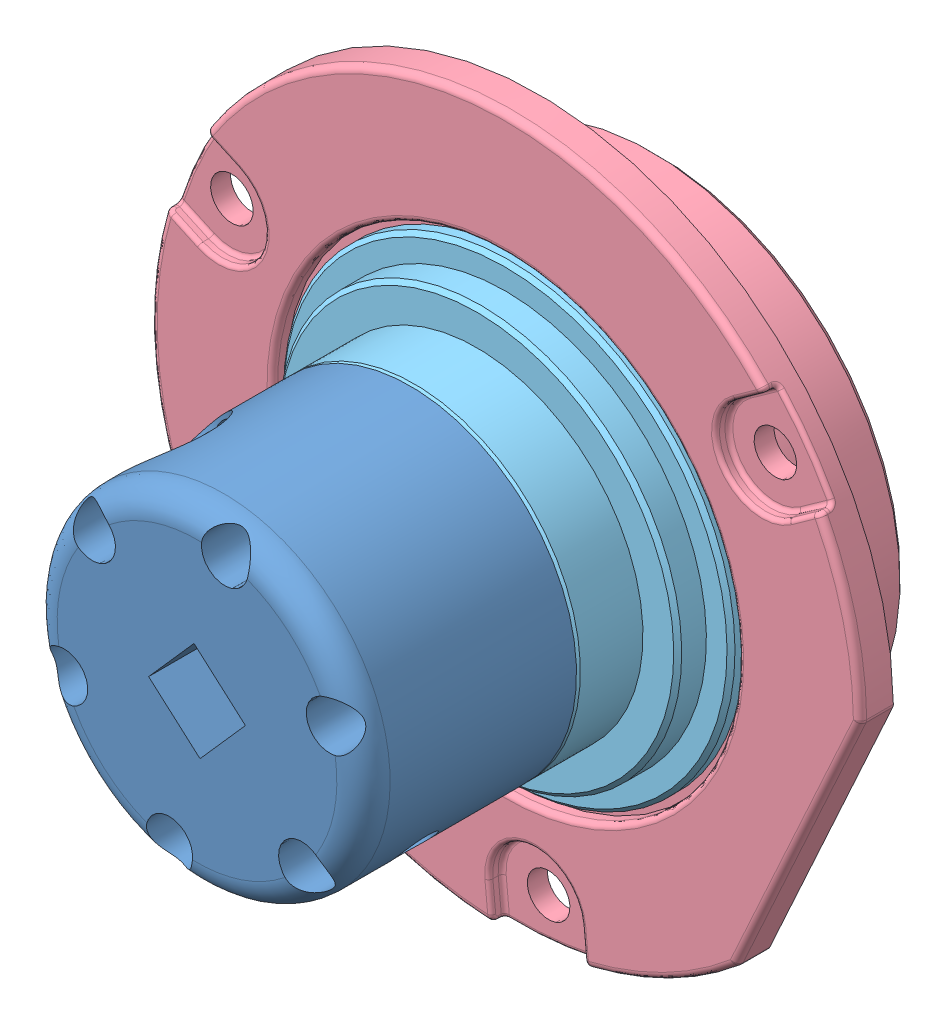
SolidWorks assembly axis, configuration 默认. Lengths in mm.
Overall size (68.34 69.57 38.65).
5 component instances, 5 part files, 11 mates.
Components (placement in the parent):
- r1-1: r1 [默认] at (-2.8699 2.4194 15) x (0.661758 0.749718 0) z (0 0 1) size (25 25 20)
- mirror-1: mirror [默认] at (-4.6302 0.5385 24.5) x (0.749718 -0.661758 0) z (0 0 1) size (4.95 5 4.93)
- m1-2: m1 [默认] at (-10.2492 8.9329 24) x (0 0 -1) z (0.661758 0.749718 0) size (8 2 8)
- motor_stator-1: motor_stator [默认] at (-2.8699 2.4194 -3.65) x (0.909658 -0.415357 0) z (-0.415357 -0.909658 0) size (50.8 11.53 53.28)
- motor_rotor-1: motor_rotor [默认] at (-2.8699 2.4194 7.85) x (-0.19824 -0.980154 0) z (-0.980154 0.19824 0) size (33.9 11.85 33.9)
Mates (geometry in assembly coordinates):
- 重合1: coincident anti-aligned: plane of r1-1 through (-6.5045 2.1929 22) normal (0.749718 -0.661758 0); plane of mirror-1 through (-3.1957 5.9415 22) normal (-0.749718 0.661758 0)
- 重合2: coincident anti-aligned: plane of r1-1 through (-2.6434 -1.2152 22) normal (0.661758 0.749718 0); plane of mirror-1 through (-4.6302 0.5385 24.5) normal (-0.661758 -0.749718 0)
- 重合3: coincident anti-aligned: plane of r1-1 through (330877.8242 374859.6806 27.15) normal (-0.530131 0.467933 0.707107); plane of mirror-1 through (-6.5045 2.1929 22) normal (0.530131 -0.467933 -0.707107)
- 重合4: coincident anti-aligned: plane of r1-1 through (-10.2492 8.9329 24) normal (-0.749718 0.661758 0); plane of m1-2 through (-10.2492 8.9329 24) normal (0.749718 -0.661758 0)
- 同心1: concentric aligned: cylinder of r1-1 through (-13.248 11.5799 24) axis (0.749718 -0.661758 0) radius 4.05; cylinder of m1-2 through (-11.7486 10.2564 24) axis (0.749718 -0.661758 0) radius 4
- 平行1: parallel anti-aligned: line of r1-1 through (0.7646 2.6459 27.15) axis (-0.661758 -0.749718 0); line of m1-2 through (-14.2157 7.1591 24.6) axis (0.661758 0.749718 0)
- 重合6: coincident anti-aligned: plane of motor_stator-1 through (-2.8699 2.4194 6.85) normal (0 0 1); plane of motor_rotor-1 through (-2.8699 2.4194 6.85) normal (0 0 -1)
- 同心4: concentric aligned: cylinder of motor_stator-1 through (-2.8699 2.4194 7.85) axis (0 0 -1) radius 26.64; cylinder of motor_rotor-1 through (-2.8699 2.4194 15) axis (0 0 -1) radius 12.49
- 重合7: coincident anti-aligned: plane of r1-1 through (-2.8699 2.4194 15) normal (0 0 -1); plane of motor_rotor-1 through (-2.8699 2.4194 15) normal (0 0 1)
- 同心5: concentric aligned: cylinder of r1-1 through (-2.8699 2.4194 35) axis (0 0 -1) radius 12.5; cylinder of motor_rotor-1 through (-2.8699 2.4194 15) axis (0 0 -1) radius 12.49
- 同心6: concentric aligned: cylinder of r1-1 through (-12.8235 -0.9238 18) axis (0 0 1) radius 1.75; cylinder of motor_rotor-1 through (-12.8235 -0.9238 15) axis (0 0 1) radius 0.8
